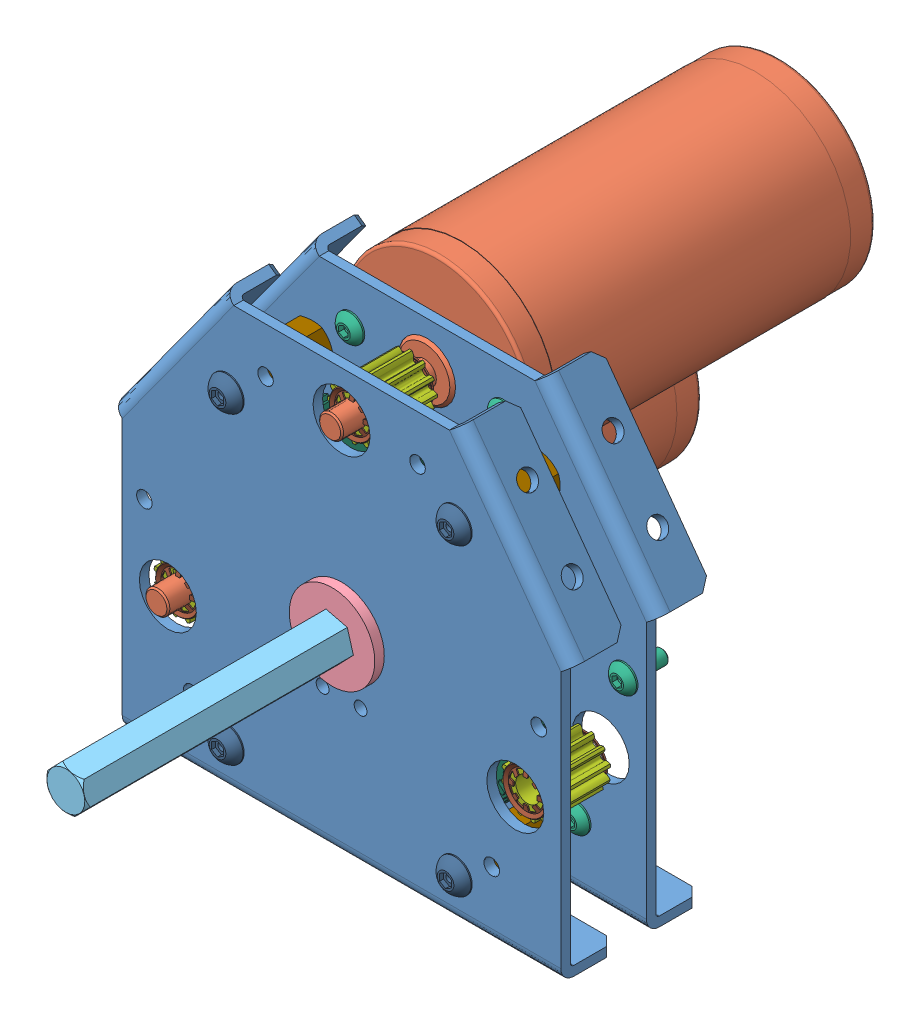
SolidWorks assembly 217-2752.20121217_1, configuration Default. Lengths in mm.
Overall size (175.78 170.45 243.24).
43 component instances, 15 part files, 0 mates.
Components (placement in the parent):
- 217-2752-001 Rev1-1: 217-2752-001 Rev1 [Default] at origin size (153.69 144.21 18.41)
- 217-2752-001 Rev1-2: 217-2752-001 Rev1 [Default] at (0 0 28.575) size (153.69 144.21 18.41)
- 217-2000 - CIM Motor-1: 217-2000 - CIM Motor [Default] at (56.8866 -18.9064 -19.05) x (-0.309017 0.951057 0) z (0 0 1) size (64.01 64.01 154.93)
- 217-2000 - CIM Motor-2: 217-2000 - CIM Motor [Default] at (35.56 170.3324 -19.05) x (-1 0 0) z (0 0 1) size (64.01 64.01 154.93)
- 217-2731-1: 217-2731 [Default] at (0 0 -3.175) x (1 0 0) z (0 -1 0) size (31.12 7.94 31.12)
- 217-2734-1: 217-2734 [Default] at (0 0 34.925) x (-0.970869 0.239612 0) z (-0.239612 -0.970869 0) size (31.12 7.94 31.12)
- 217-2454-004 Rev1-1: 217-2454-004 Rev1 [Default] at (0 0 60.3758) x (0 0 1) z (-0.692944 -0.720991 0) size (140.21 12.7 16.13)
- SBS1_SBS1032-0500ZC-1: SBS1_SBS1032-0500ZC [Default] at (-25.4 61.0362 5.7404) x (0 0 -1) z (1 0 0) size (15.78 9.29 9.24)
- 217-2614-001_12t-1: 217-2614-001_12t [Default] at (0 61.0362 18.1045) x (0 1 0) z (0 0 1) size (18.29 18.29 19)
- 217-2737 Rev1-1: 217-2737 Rev1 [Default] at (0 0 11.1633) x (0.855146 -0.518388 0) z (0 0 1) size (25.39 25.4 7.82)
- 217-2617-002 Rev1_91780A359-1: 217-2617-002 Rev1_91780A359 [Default] at (38.1 -51.435 15.875) x (0.856767 0.515704 0) z (0 0 1) size (12.7 14.66 25.4)
- SBS1_SBS2520-0500SS-1: SBS1_SBS2520-0500SS [Default] at (38.1 50.165 -3.3528) x (0 0 1) z (-0.923728 -0.383049 0) size (16.73 11.22 11.17)
- 217-2617-002 Rev1_91780A359-2: 217-2617-002 Rev1_91780A359 [Default] at (38.1 50.165 15.875) size (12.7 14.66 25.4)
- 217-2617-002 Rev1_91780A359-3: 217-2617-002 Rev1_91780A359 [Default] at (-38.1 -51.435 15.875) x (0.856767 0.515704 0) z (0 0 1) size (12.7 14.66 25.4)
- 217-2617-002 Rev1_91780A359-4: 217-2617-002 Rev1_91780A359 [Default] at (-38.1 50.165 15.875) x (0.856767 0.515704 0) z (0 0 1) size (12.7 14.66 25.4)
- SBS1_SBS2520-0500SS-2: SBS1_SBS2520-0500SS [Default] at (38.1 50.165 35.1028) x (0 0 -1) z (1 0 0) size (16.73 11.22 11.17)
- SBS1_SBS2520-0500SS-3: SBS1_SBS2520-0500SS [Default] at (-38.1 -51.435 35.1028) x (0 0 -1) z (1 0 0) size (16.73 11.22 11.17)
- SBS1_SBS2520-0500SS-4: SBS1_SBS2520-0500SS [Default] at (-38.1 50.165 35.1028) x (0 0 -1) z (1 0 0) size (16.73 11.22 11.17)
- SBS1_SBS2520-0500SS-5: SBS1_SBS2520-0500SS [Default] at (38.1 -51.435 35.1028) x (0 0 -1) z (1 0 0) size (16.73 11.22 11.17)
- SBS1_SBS2520-0500SS-6: SBS1_SBS2520-0500SS [Default] at (38.1 -51.435 -3.3528) x (0 0 1) z (0.95771 0.287735 0) size (16.73 11.22 11.17)
- SBS1_SBS2520-0500SS-7: SBS1_SBS2520-0500SS [Default] at (-38.1 -51.435 -3.3528) x (0 0 1) z (0.95771 0.287735 0) size (16.73 11.22 11.17)
- SBS1_SBS2520-0500SS-8: SBS1_SBS2520-0500SS [Default] at (-38.1 50.165 -3.3528) x (0 0 1) z (0.95771 0.287735 0) size (16.73 11.22 11.17)
- 217-2614-001_12t-2: 217-2614-001_12t [Default] at (-58.0489 -18.8612 18.1045) x (0.951057 0.309017 0) z (0 0 1) size (18.29 18.29 19)
- 217-2614-001_12t-3: 217-2614-001_12t [Default] at (58.0489 -18.8612 18.1045) x (0.951057 -0.309017 0) z (0 0 1) size (18.29 18.29 19)
- 217-2614-002_98430A132-1: 217-2614-002_98430A132 [Default] at (-58.0489 -18.8612 27.6041) x (0 0 1) z (-1 0 0) size (1.2 14.83 14.83)
- 217-2614-002_98430A132-2: 217-2614-002_98430A132 [Default] at (-58.0489 -18.8612 7.5381) x (0 0 1) z (-1 0 0) size (1.2 14.83 14.83)
- 217-2614-002_98430A132-3: 217-2614-002_98430A132 [Default] at (0 61.0362 27.6041) x (0 0 1) z (-1 0 0) size (1.2 14.83 14.83)
- 217-2614-002_98430A132-4: 217-2614-002_98430A132 [Default] at (0 61.0362 7.5381) x (0 0 1) z (-1 0 0) size (1.2 14.83 14.83)
- 217-2614-002_98430A132-5: 217-2614-002_98430A132 [Default] at (58.0489 -18.8612 27.6041) x (0 0 1) z (-1 0 0) size (1.2 14.83 14.83)
- 217-2614-002_98430A132-6: 217-2614-002_98430A132 [Default] at (58.0489 -18.8612 7.5381) x (0 0 1) z (-1 0 0) size (1.2 14.83 14.83)
- SBS1_SBS1032-0500ZC-2: SBS1_SBS1032-0500ZC [Default] at (25.4 61.0362 5.7404) x (0 0 -1) z (1 0 0) size (15.78 9.29 9.24)
- SBS1_SBS1032-0500ZC-3: SBS1_SBS1032-0500ZC [Default] at (65.8979 5.2956 5.7404) x (0 0 -1) z (1 0 0) size (15.78 9.29 9.24)
- SBS1_SBS1032-0500ZC-4: SBS1_SBS1032-0500ZC [Default] at (50.1998 -43.0181 5.7404) x (0 0 -1) z (1 0 0) size (15.78 9.29 9.24)
- SBS1_SBS1032-0500ZC-5: SBS1_SBS1032-0500ZC [Default] at (-50.1998 -43.0181 5.7404) x (0 0 -1) z (1 0 0) size (15.78 9.29 9.24)
- SBS1_SBS1032-0500ZC-6: SBS1_SBS1032-0500ZC [Default] at (-65.8979 5.2956 5.7404) x (0 0 -1) z (1 0 0) size (15.78 9.29 9.24)
- 217-2745-002 Rev1-1: 217-2745-002 Rev1 [Default] at (0 0 -39.6748) size (25.4 38.1 1.57)
- 217-2428-005 Rev1-1: 217-2428-005 Rev1 [Default] at (6.35 -19.05 -19.05) x (0.995022 0.099653 0) z (-0.099653 0.995022 0) size (7.33 38.98 6.35)
- 217-2428-005 Rev1-2: 217-2428-005 Rev1 [Default] at (-6.35 -19.05 -19.05) x (0.995022 0.099653 0) z (-0.099653 0.995022 0) size (7.33 38.98 6.35)
- SBS1_SBS0832-0500SS-1: SBS1_SBS0832-0500SS [Default] at (-6.35 -19.05 -41.8846) x (0 0 1) z (-1 0 0) size (15.36 8.02 7.99)
- SBS1_SBS0832-0500SS-2: SBS1_SBS0832-0500SS [Default] at (6.35 -19.05 -41.8846) x (0 0 1) z (-1 0 0) size (15.36 8.02 7.99)
- SBS1_SBS0832-0500SS-3: SBS1_SBS0832-0500SS [Default] at (6.35 -19.05 5.3848) x (0 0 -1) z (1 0 0) size (15.36 8.02 7.99)
- SBS1_SBS0832-0500SS-4: SBS1_SBS0832-0500SS [Default] at (-6.35 -19.05 5.3848) x (0 0 -1) z (1 0 0) size (15.36 8.02 7.99)
- 217-2717-001_84t-1: 217-2717-001_84t [Default] at (0 0 20.6629) x (0.720991 -0.692944 0) z (0 0 1) size (109.49 109.49 12.65)
